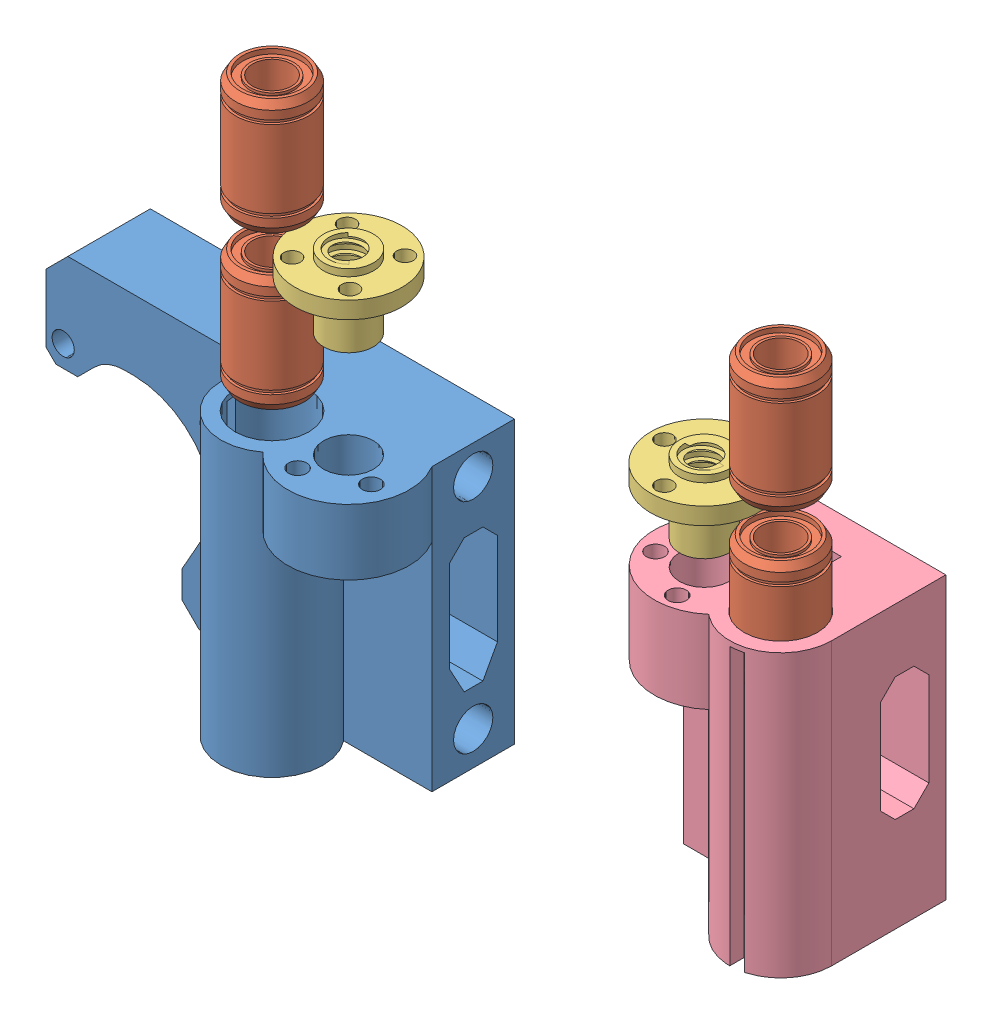
SolidWorks assembly Step5, configuration Default. Lengths in mm.
Overall size (151.67 118.39 55.68).
8 component instances, 4 part files, 7 mates.
Components (placement in the parent):
- Motor Mount-1: Motor Mount [Default] at (-5.2466 102.3397 79.6309) x (-1 0 0) z (0 0 -1) size (81.27 58 36)
- lm8uu-1: lm8uu [Default] at (-31.6736 119.2465 86.1309) x (0.992787 0 -0.119895) z (0 -1 0) size (15 15 24)
- lm8uu-2: lm8uu [Default] at (-31.6736 150.7306 86.1309) x (0.925343 0 -0.379132) z (0 -1 0) size (15 15 24)
- flanged lead screw nut-1: flanged lead screw nut [Default] at (-15.9237 137.7293 86.1309) x (0.725187 0 0.688552) z (0 -1 0) size (22 22 19.88)
- Right z holder-2: Right z holder [Default] at (48.4694 73.3397 45.9983) x (0 1 0) z (1 0 0) size (58 34.5 38.04)
- lm8uu-3: lm8uu [Default] at (56.4694 104.067 69.4983) x (0.990405 0 -0.138193) z (0 -1 0) size (15 15 24)
- lm8uu-4: lm8uu [Default] at (56.4694 136.7787 69.4983) x (1 0 -0.000041) z (0 -1 0) size (15 15 24)
- flanged lead screw nut-2: flanged lead screw nut [Default] at (40.7193 120.9933 69.4983) x (1 0 -0.000328) z (0 -1 0) size (22 22 19.88)
Mates (geometry in assembly coordinates):
- Concentric7: concentric aligned: cylinder of Motor Mount-1 through (-15.9237 88.8397 86.1309) axis (0 1 0) radius 12.5; cylinder of flanged lead screw nut-1 through (-15.9237 137.7293 86.1309) axis (0 1 0) radius 11
- Concentric8: concentric aligned: cylinder of Motor Mount-1 through (-31.6736 44.3397 86.1309) axis (0 1 0) radius 7.575; cylinder of lm8uu-1 through (-31.6736 107.2465 86.1309) axis (0 1 0) radius 7.5
- Concentric9: concentric aligned: cylinder of Motor Mount-1 through (-31.6736 44.3397 86.1309) axis (0 1 0) radius 7.575; cylinder of lm8uu-2 through (-31.6736 138.7306 86.1309) axis (0 1 0) radius 7.5
- Concentric10: concentric aligned: cylinder of Right z holder-2 through (40.7193 44.3397 69.4983) axis (0 1 0) radius 5.125; cylinder of flanged lead screw nut-2 through (40.7193 122.4433 69.4983) axis (0 1 0) radius 5.125
- Concentric11: concentric aligned: cylinder of Right z holder-2 through (56.4694 44.3397 69.4983) axis (0 1 0) radius 7.575; cylinder of lm8uu-3 through (56.4694 92.067 69.4983) axis (0 1 0) radius 7.5
- Concentric12: concentric aligned: cylinder of lm8uu-3 through (56.4694 92.067 69.4983) axis (0 1 0) radius 7.5; cylinder of lm8uu-4 through (56.4694 124.7787 69.4983) axis (0 1 0) radius 7.5
- Coincident5: coincident aligned: plane of Motor Mount-1 through (-5.2466 102.3397 62.6309) normal (0 1 0); plane of Right z holder-2 through (66.9694 102.3397 62.9983) normal (0 1 0)
